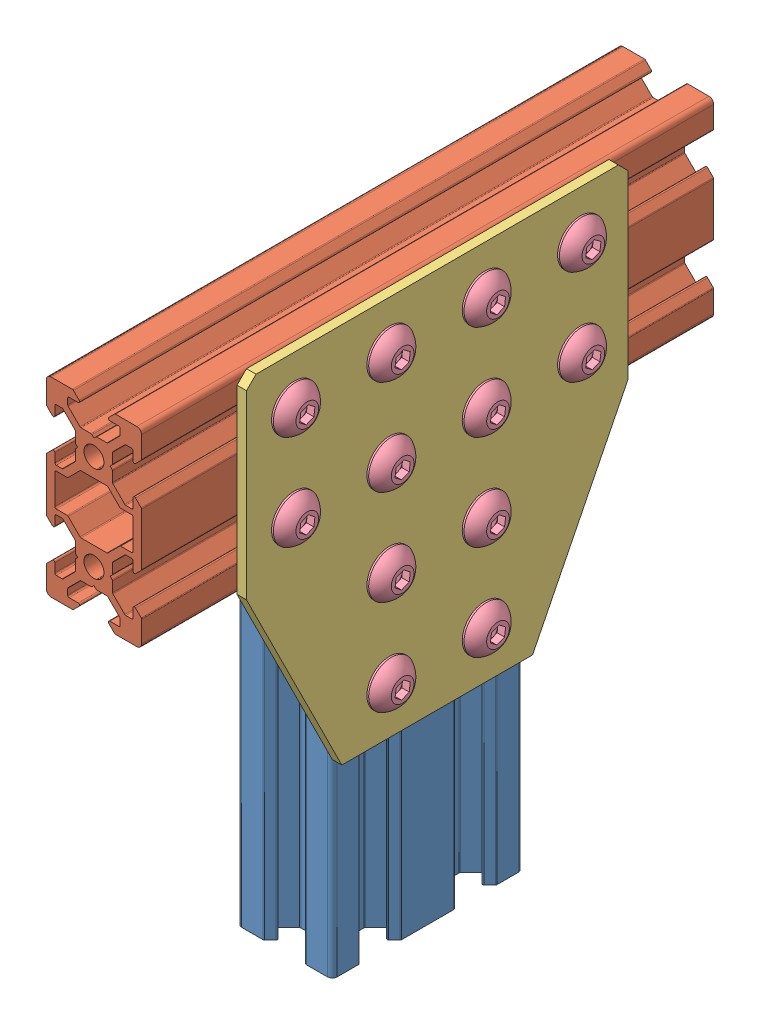
SolidWorks assembly Т-пластина 20 серия 4х4 12отв 80х80х2 усил СБ, configuration По умолчанию. Lengths in mm.
Overall size (24.75 120 120).
15 component instances, 4 part files, 33 mates.
Components (placement in the parent):
- 204090-1: 204090 [По умолчанию] at (-10 0 -10) x (0 0 -1) z (0 1 0) size (40 20 80)
- 2040120-1: 2040120 [По умолчанию] at (-10 110 -80) x (0 -1 0) z (0 0 1) size (40 20 120)
- Т-пластина 20 серия 4х4 12отв 80х80х2 усил.-1: Т-пластина 20 серия 4х4 12отв 80х80х2 усил. [По умолчанию] at (0 40 -20) x (0 0 -1) z (0 -1 0) size (80 2 80)
- socket button head screw_iso-1: socket button head screw_iso [ISO 7380 - M5 x 10 - 10N] at (4.75 110 10) x (-1 0 0) z (0 0.924225 0.381849) size (12.75 9.5 9.5)
- socket button head screw_iso-2: socket button head screw_iso [ISO 7380 - M5 x 10 - 10N] at (4.75 110 -10) x (-1 0 0) z (0 0.924225 0.381849) size (12.75 9.5 9.5)
- socket button head screw_iso-3: socket button head screw_iso [ISO 7380 - M5 x 10 - 10N] at (4.75 110 -30) x (-1 0 0) z (0 0.924225 0.381849) size (12.75 9.5 9.5)
- socket button head screw_iso-4: socket button head screw_iso [ISO 7380 - M5 x 10 - 10N] at (4.75 110 -50) x (-1 0 0) z (0 0.924225 0.381849) size (12.75 9.5 9.5)
- socket button head screw_iso-5: socket button head screw_iso [ISO 7380 - M5 x 10 - 10N] at (4.75 90 -50) x (-1 0 0) z (0 0.924225 0.381849) size (12.75 9.5 9.5)
- socket button head screw_iso-6: socket button head screw_iso [ISO 7380 - M5 x 10 - 10N] at (4.75 90 -30) x (-1 0 0) z (0 0.924225 0.381849) size (12.75 9.5 9.5)
- socket button head screw_iso-7: socket button head screw_iso [ISO 7380 - M5 x 10 - 10N] at (4.75 90 -10) x (-1 0 0) z (0 0.924225 0.381849) size (12.75 9.5 9.5)
- socket button head screw_iso-8: socket button head screw_iso [ISO 7380 - M5 x 10 - 10N] at (4.75 90 10) x (-1 0 0) z (0 0.924225 0.381849) size (12.75 9.5 9.5)
- socket button head screw_iso-9: socket button head screw_iso [ISO 7380 - M5 x 10 - 10N] at (4.75 70 -10) x (-1 0 0) z (0 0.924225 0.381849) size (12.75 9.5 9.5)
- socket button head screw_iso-10: socket button head screw_iso [ISO 7380 - M5 x 10 - 10N] at (4.75 70 -30) x (-1 0 0) z (0 0.924225 0.381849) size (12.75 9.5 9.5)
- socket button head screw_iso-11: socket button head screw_iso [ISO 7380 - M5 x 10 - 10N] at (4.75 50 -10) x (-1 0 0) z (0 0.924225 0.381849) size (12.75 9.5 9.5)
- socket button head screw_iso-12: socket button head screw_iso [ISO 7380 - M5 x 10 - 10N] at (4.75 50 -30) x (-1 0 0) z (0 0.924225 0.381849) size (12.75 9.5 9.5)
Mates (geometry in assembly coordinates):
- Совпадение1: coincident anti-aligned: plane of 204090-1 through (-10 0 -10) normal (0 -1 0)
- Совпадение2: coincident aligned: plane of 204090-1 through (0 80 -25.6) normal (1 0 0)
- Совпадение3: coincident aligned: plane of 204090-1 through (-20 80 0) normal (0 0 1)
- Совпадение4: coincident anti-aligned: plane of 204090-1 through (-10 80 -10) normal (0 1 0); plane of 2040120-1 through (-20 80 40) normal (0 -1 0)
- Совпадение5: coincident aligned: plane of 204090-1 through (0 80 -25.6) normal (1 0 0); plane of 2040120-1 through (0 80 40) normal (1 0 0)
- Совпадение6: coincident anti-aligned: plane of 2040120-1 through (0 94.4 40) normal (1 0 0); plane of Т-пластина 20 серия 4х4 12отв 80х80х2 усил.-1 through (0 40 -20) normal (-1 0 0)
- Совпадение7: coincident aligned: plane of 2040120-1 through (0 120 40) normal (0 1 0); plane of Т-пластина 20 серия 4х4 12отв 80х80х2 усил.-1 through (2 120 20) normal (0 1 0)
- Расстояние1: distance = 20 mm aligned: plane of 2040120-1 through (-10 110 40) normal (0 0 1); plane of Т-пластина 20 серия 4х4 12отв 80х80х2 усил.-1 through (2 120 20) normal (0 0 1)
- Совпадение9: coincident: plane of 204090-1 through (0 80 0) normal (0 0 1); line of Т-пластина 20 серия 4х4 12отв 80х80х2 усил.-1 through (2 40 0) axis (-1 0 0)
- Концентричный1: concentric aligned: cylinder of Т-пластина 20 серия 4х4 12отв 80х80х2 усил.-1 through (2 110 10) axis (1 0 0) radius 2.75; cylinder of socket button head screw_iso-1 through (4.75 110 10) axis (1 0 0) radius 4.75
- Совпадение10: coincident anti-aligned: plane of Т-пластина 20 серия 4х4 12отв 80х80х2 усил.-1 through (2 40 -20) normal (1 0 0); plane of socket button head screw_iso-1 through (2 109.0454 12.3106) normal (-1 0 0)
- Концентричный2: concentric aligned: cylinder of Т-пластина 20 серия 4х4 12отв 80х80х2 усил.-1 through (2 110 -10) axis (1 0 0) radius 2.75; cylinder of socket button head screw_iso-2 through (4.75 110 -10) axis (1 0 0) radius 4.75
- Совпадение11: coincident anti-aligned: plane of Т-пластина 20 серия 4х4 12отв 80х80х2 усил.-1 through (2 40 -20) normal (1 0 0); plane of socket button head screw_iso-2 through (2 109.0454 -7.6894) normal (-1 0 0)
- Концентричный3: concentric aligned: cylinder of Т-пластина 20 серия 4х4 12отв 80х80х2 усил.-1 through (2 110 -30) axis (1 0 0) radius 2.75; cylinder of socket button head screw_iso-3 through (4.75 110 -30) axis (1 0 0) radius 4.75
- Совпадение12: coincident anti-aligned: plane of Т-пластина 20 серия 4х4 12отв 80х80х2 усил.-1 through (2 40 -20) normal (1 0 0); plane of socket button head screw_iso-3 through (2 109.0454 -27.6894) normal (-1 0 0)
- Концентричный4: concentric aligned: cylinder of Т-пластина 20 серия 4х4 12отв 80х80х2 усил.-1 through (2 110 -50) axis (1 0 0) radius 2.75; cylinder of socket button head screw_iso-4 through (4.75 110 -50) axis (1 0 0) radius 4.75
- Совпадение13: coincident anti-aligned: plane of Т-пластина 20 серия 4х4 12отв 80х80х2 усил.-1 through (2 40 -20) normal (1 0 0); plane of socket button head screw_iso-4 through (2 109.0454 -47.6894) normal (-1 0 0)
- Концентричный5: concentric aligned: cylinder of Т-пластина 20 серия 4х4 12отв 80х80х2 усил.-1 through (2 90 -50) axis (1 0 0) radius 2.75; cylinder of socket button head screw_iso-5 through (4.75 90 -50) axis (1 0 0) radius 4.75
- Совпадение14: coincident anti-aligned: plane of Т-пластина 20 серия 4х4 12отв 80х80х2 усил.-1 through (2 40 -20) normal (1 0 0); plane of socket button head screw_iso-5 through (2 89.0454 -47.6894) normal (-1 0 0)
- Концентричный6: concentric aligned: cylinder of Т-пластина 20 серия 4х4 12отв 80х80х2 усил.-1 through (2 90 -30) axis (1 0 0) radius 2.75; cylinder of socket button head screw_iso-6 through (4.75 90 -30) axis (1 0 0) radius 4.75
- Совпадение15: coincident anti-aligned: plane of Т-пластина 20 серия 4х4 12отв 80х80х2 усил.-1 through (2 40 -20) normal (1 0 0); plane of socket button head screw_iso-6 through (2 89.0454 -27.6894) normal (-1 0 0)
- Концентричный7: concentric aligned: cylinder of Т-пластина 20 серия 4х4 12отв 80х80х2 усил.-1 through (2 90 -10) axis (1 0 0) radius 2.75; cylinder of socket button head screw_iso-7 through (4.75 90 -10) axis (1 0 0) radius 4.75
- Совпадение16: coincident anti-aligned: plane of Т-пластина 20 серия 4х4 12отв 80х80х2 усил.-1 through (2 40 -20) normal (1 0 0); plane of socket button head screw_iso-7 through (2 89.0454 -7.6894) normal (-1 0 0)
- Концентричный8: concentric aligned: cylinder of Т-пластина 20 серия 4х4 12отв 80х80х2 усил.-1 through (2 90 10) axis (1 0 0) radius 2.75; cylinder of socket button head screw_iso-8 through (4.75 90 10) axis (1 0 0) radius 4.75
- Совпадение17: coincident anti-aligned: plane of Т-пластина 20 серия 4х4 12отв 80х80х2 усил.-1 through (2 40 -20) normal (1 0 0); plane of socket button head screw_iso-8 through (2 89.0454 12.3106) normal (-1 0 0)
- Концентричный9: concentric aligned: cylinder of Т-пластина 20 серия 4х4 12отв 80х80х2 усил.-1 through (2 70 -10) axis (1 0 0) radius 2.75; cylinder of socket button head screw_iso-9 through (4.75 70 -10) axis (1 0 0) radius 4.75
- Совпадение18: coincident anti-aligned: plane of Т-пластина 20 серия 4х4 12отв 80х80х2 усил.-1 through (2 40 -20) normal (1 0 0); plane of socket button head screw_iso-9 through (2 69.0454 -7.6894) normal (-1 0 0)
- Концентричный10: concentric aligned: cylinder of Т-пластина 20 серия 4х4 12отв 80х80х2 усил.-1 through (2 70 -30) axis (1 0 0) radius 2.75; cylinder of socket button head screw_iso-10 through (4.75 70 -30) axis (1 0 0) radius 4.75
- Совпадение19: coincident anti-aligned: plane of Т-пластина 20 серия 4х4 12отв 80х80х2 усил.-1 through (2 40 -20) normal (1 0 0); plane of socket button head screw_iso-10 through (2 69.0454 -27.6894) normal (-1 0 0)
- Концентричный11: concentric aligned: cylinder of Т-пластина 20 серия 4х4 12отв 80х80х2 усил.-1 through (2 50 -10) axis (1 0 0) radius 2.75; cylinder of socket button head screw_iso-11 through (4.75 50 -10) axis (1 0 0) radius 4.75
- Совпадение20: coincident anti-aligned: plane of Т-пластина 20 серия 4х4 12отв 80х80х2 усил.-1 through (2 40 -20) normal (1 0 0); plane of socket button head screw_iso-11 through (2 49.0454 -7.6894) normal (-1 0 0)
- Концентричный12: concentric aligned: cylinder of Т-пластина 20 серия 4х4 12отв 80х80х2 усил.-1 through (2 50 -30) axis (1 0 0) radius 2.75; cylinder of socket button head screw_iso-12 through (4.75 50 -30) axis (1 0 0) radius 4.75
- Совпадение21: coincident anti-aligned: plane of Т-пластина 20 серия 4х4 12отв 80х80х2 усил.-1 through (2 40 -20) normal (1 0 0); plane of socket button head screw_iso-12 through (2 49.0454 -27.6894) normal (-1 0 0)
